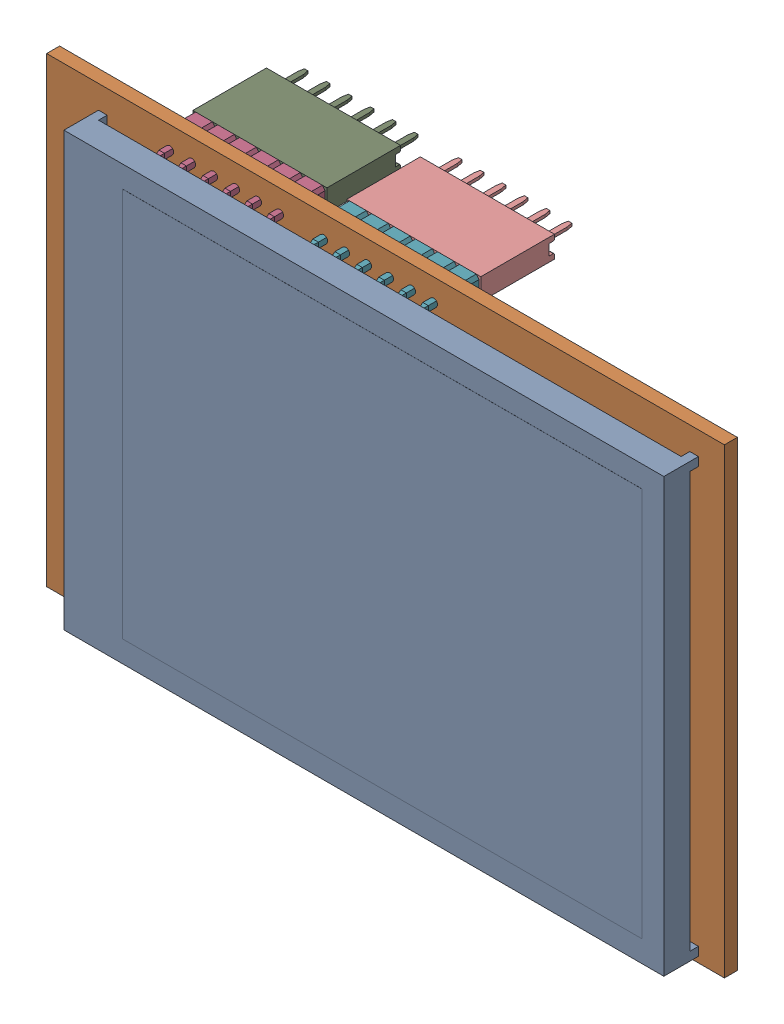
SolidWorks assembly LCDassembly, configuration Default. Lengths in mm.
Overall size (78.3 53.34 20.75).
9 component instances, 5 part files, 0 mates.
Components (placement in the parent):
- baseboard-1: baseboard [Default] at (-5.088 0 11.04) x (-1 0 0) z (0 0 1) size (78.3 53.34 6.51)
- HEADER8-1: HEADER8 [Default] at (-16.01 -24.1265 0) x (-1 0 0) z (0 1 0) size (20.57 11.7 2.5)
- SIL6-1: SIL6 [Default] at (-18.55 24.13 11.04) x (-1 0 0) z (0 1 0) size (15.24 11.2 2.5)
- SIL8-1: SIL8 [Default] at (-16.01 -24.13 11.04) x (-1 0 0) z (0 1 0) size (20.32 11.2 2.5)
- SIL8-2: SIL8 [Default] at (5.834 -24.13 11.04) x (-1 0 0) z (0 1 0) size (20.32 11.2 2.5)
- SIL6-2: SIL6 [Default] at (-0.77 24.13 11.04) x (-1 0 0) z (0 1 0) size (15.24 11.2 2.5)
- HEADER8-2: HEADER8 [Default] at (5.834 -24.1265 0) x (-1 0 0) z (0 1 0) size (20.57 11.7 2.5)
- HEADER6-1: HEADER6 [Default] at (-18.55 24.1335 0) x (-1 0 0) z (0 1 0) size (15.49 11.7 2.5)
- HEADER6-2: HEADER6 [Default] at (-0.77 24.1335 0) x (-1 0 0) z (0 1 0) size (15.49 11.7 2.5)
